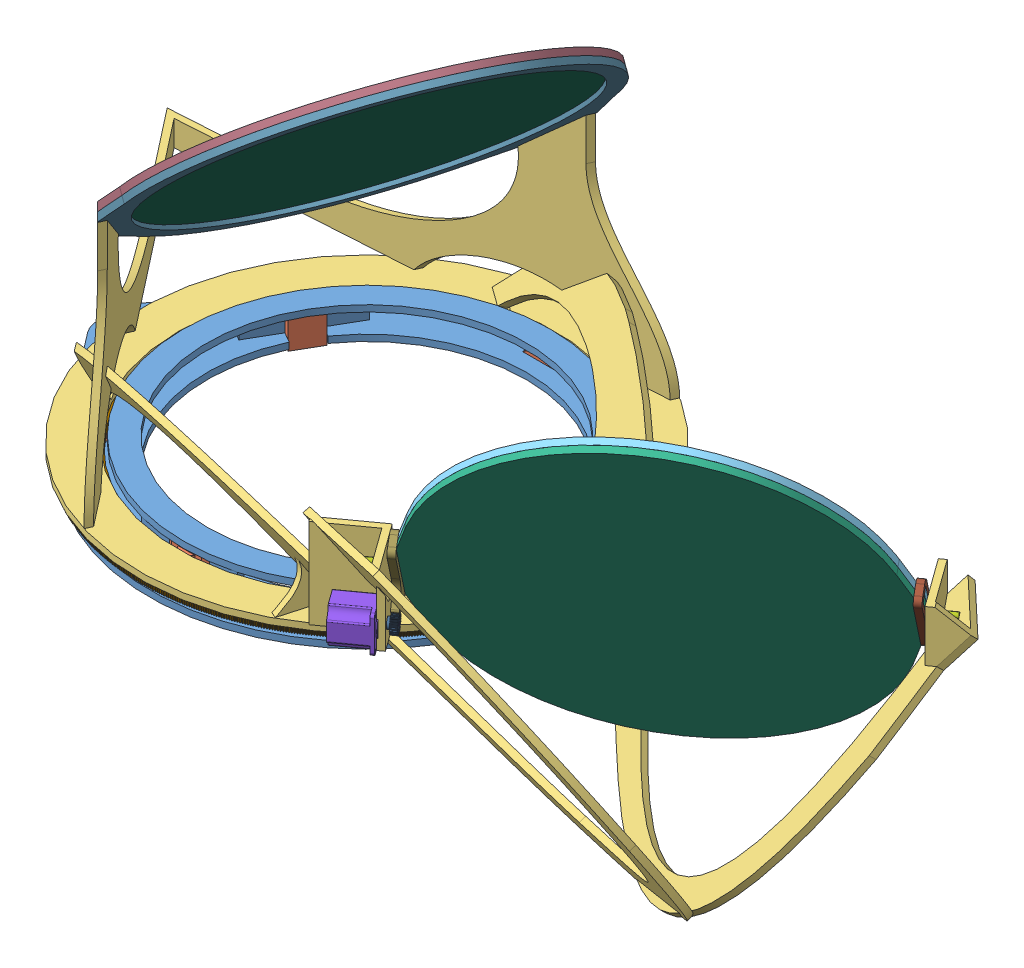
SolidWorks assembly Base assembly, configuration Default. Lengths in mm.
Overall size (1914.99 823.14 1392.98).
25 component instances, 15 part files, 49 mates.
Components (placement in the parent):
- Base-1: Base [Default] at (-52.5537 -31.3626 49.0391) size (745.7 50 680)
- McMaster 2303T11-1: McMaster 2303T11 [Default] at (-309.9581 -23.7438 197.6516) x (0.5 0 0.866025) z (-0.866025 0 0.5) size (62.32 36.6 44.45)
- McMaster 2303T11-2: McMaster 2303T11 [Default] at (-52.5537 -14.6635 323.9579) x (1 0 0) z (0 -1 0) size (62.32 36.6 44.45)
- McMaster 2303T11-3: McMaster 2303T11 [Default] at (-52.5537 -23.7438 -248.1859) size (62.32 36.6 44.45)
- McMaster 2303T11-4: McMaster 2303T11 [Default] at (204.8507 -23.7438 197.6516) x (0.5 0 -0.866025) z (0.866025 0 0.5) size (62.32 36.6 44.45)
- McMaster 2303T11-5: McMaster 2303T11 [Default] at (185.5329 -14.6635 -88.4202) x (0.5 0 0.866025) z (0 1 0) size (62.32 36.6 44.45)
- McMaster 2303T11-6: McMaster 2303T11 [Default] at (-290.6404 -14.6635 -88.4202) x (0.5 0 -0.866025) z (0 1 0) size (62.32 36.6 44.45)
- Plywood Construction-1-1: Plywood Construction-1 [Default] at (-52.5537 11.3374 49.0391) x (0.912295 0 0.409533) z (-0.409533 0 0.912295) size (1754.25 687.65 739.41)
- Mirror Assembly-2: Mirror Assembly [Default] at (781.8584 416.3374 423.6103) x (-0.810814 0 0.585304) z (-0.299925 -0.858731 -0.415482) size (600 20 760)
  - Mirror-1: Mirror [Default] at origin size (550 4 730)
  - Mirror Front-1: Mirror Front [Default] at origin size (600 10 760)
  - Mirror Back-1: Mirror Back [Default] x (-1 0 0) z (0 0 1) size (600 10 760)
- Primary Mirror Axle-1: Primary Mirror Axle [Default] at (1005.9697 404.2871 238.5997) x (0.299925 0.858731 0.415482) z (-0.502619 0.512426 -0.696271) size (40 45 20)
- Primary Mirror Axle-2: Primary Mirror Axle [Default] at (545.7501 394.0386 592.0016) x (0.299925 0.858731 0.415482) z (0.502619 -0.512426 0.696271) size (40 45 20)
- Stepper (Sparkfun 125oz)-1: Stepper (Sparkfun 125oz) [Default] at (509.4506 317.3629 674.4254) x (-0.585304 0 -0.810814) z (0 -1 0) size (56.4 77.1 56.4)
- Stepper (Sparkfun 125oz)-2: Stepper (Sparkfun 125oz) [Default] at (-443.2537 -75.3626 20.8391) x (0 0 1) z (-1 0 0) size (56.4 77.1 56.4)
- 700 teeth-1: 700 teeth [Gear Blank] at (-52.5537 1.3374 49.0391) x (0.924366 0 -0.381507) z (0 -1 0) size (702 702 10)
- A1Z2MYZ1002506-1: A1Z2MYZ1002506 [Default] at (-415.0537 -5.1626 49.0391) x (0 -1 0) z (0.987676 0 0.156512) size (17.51 26.95 26.99)
- A1Z2MYZ1002506-2: A1Z2MYZ1002506 [Default] at (551.8101 345.5629 609.0673) x (-0.810814 0 0.585304) z (0.490533 0.545544 0.679529) size (17.51 26.95 26.99)
- El mirror side bracket-2: El mirror side bracket [Default] at (1015.9029 355.8461 235.2748) x (0.299925 0.858731 0.415482) z (0.502619 -0.512426 0.696271) size (120 10 35)
- Gear_Blank_V2-1: Gear_Blank_V2 [Gear Blank] at (546.7224 416.3374 593.3485) x (0.502619 -0.512426 0.696271) z (-0.810814 0 0.585304) size (60.92 121 10)
- Secondary Mirror-1: Secondary Mirror [Default] at (82.1211 342.156 -39.8262) x (0.409533 0 -0.912295) z (0.64509 0.707107 0.289584) size (853.84 20 760)
  - Secondary Mirror Back-1: Secondary Mirror Back [Default] at (-136.2253 113.5977 -8.6893) size (591.15 10 760)
  - Secondary Mirror Front-1: Secondary Mirror Front [Default] at (-136.2253 113.5977 -8.6893) x (-1 0 0) z (0 0 1) size (592.25 10 760)
  - Secondary Mirror-1: Secondary Mirror [Default] at (-136.2253 113.5977 -8.6893) x (-1 0 0) z (0 0 1) size (832.72 4 730)
Mates (geometry in assembly coordinates):
- Coincident1: coincident anti-aligned: plane of Base-1 through (-318.0931 -21.3626 228.0116) normal (-0.5 0 -0.866025); plane of McMaster 2303T11-1 through (-318.0931 -21.3626 228.0116) normal (0.5 0 0.866025)
- Coincident2: coincident anti-aligned: plane of Base-1 through (-279.5982 -21.3626 205.7866) normal (-0.866025 0 0.5); plane of McMaster 2303T11-1 through (-290.7107 -23.7438 186.5391) normal (0.866025 0 -0.5)
- Coincident3: coincident anti-aligned: plane of Base-1 through (-52.5537 -21.3626 49.0391) normal (0 1 0); plane of McMaster 2303T11-1 through (-344.7855 -21.3626 181.7789) normal (0 -1 0)
- Coincident4: coincident anti-aligned: plane of Base-1 through (-30.3287 7.5615 296.3391) normal (-1 0 0); plane of McMaster 2303T11-2 through (-30.3287 -36.8885 326.3391) normal (1 0 0)
- Coincident5: coincident anti-aligned: plane of Base-1 through (-30.3287 7.5615 296.3391) normal (0 -1 0); plane of McMaster 2303T11-2 through (-52.5537 7.5615 323.9579) normal (0 1 0)
- Coincident6: coincident: plane of Base-1 through (-30.3037 18.6374 326.3391) normal (0 0 1); plane of McMaster 2303T11-2 through (-83.7136 -36.8885 326.3391) normal (0 0 -1)
- Coincident7: coincident anti-aligned: plane of Base-1 through (-74.7787 -21.3626 -270.4109) normal (0 0 1); plane of McMaster 2303T11-3 through (-52.5537 -23.7438 -270.4109) normal (0 0 -1)
- Coincident8: coincident anti-aligned: plane of Base-1 through (-52.5537 -21.3626 49.0391) normal (0 1 0); plane of McMaster 2303T11-3 through (-21.3939 -21.3626 -225.9609) normal (0 -1 0)
- Coincident9: coincident anti-aligned: plane of Base-1 through (-30.3287 -21.3626 -270.4109) normal (-1 0 0); plane of McMaster 2303T11-3 through (-30.3287 -21.3626 -225.9609) normal (1 0 0)
- Coincident10: coincident anti-aligned: plane of Base-1 through (196.7157 -21.3626 167.2917) normal (0.866025 0 0.5); plane of McMaster 2303T11-4 through (185.6032 -23.7438 186.5391) normal (-0.866025 0 -0.5)
- Coincident11: coincident anti-aligned: plane of Base-1 through (235.2106 -21.3626 189.5167) normal (-0.5 0 0.866025); plane of McMaster 2303T11-4 through (235.2106 -21.3626 189.5167) normal (0.5 0 -0.866025)
- Coincident12: coincident anti-aligned: plane of Base-1 through (-52.5537 -21.3626 49.0391) normal (0 1 0); plane of McMaster 2303T11-4 through (208.5182 -21.3626 235.7494) normal (0 -1 0)
- Coincident13: coincident anti-aligned: plane of Base-1 through (150.5018 7.5615 -93.8583) normal (0 -1 0); plane of McMaster 2303T11-5 through (185.5329 7.5615 -88.4202) normal (0 1 0)
- Coincident14: coincident anti-aligned: plane of Base-1 through (172.7268 7.5615 -55.3634) normal (-0.5 0 -0.866025); plane of McMaster 2303T11-5 through (198.7076 7.5615 -70.3634) normal (0.5 0 0.866025)
- Coincident15: coincident anti-aligned: plane of Base-1 through (176.4701 18.6374 -108.8799) normal (0.866025 0 -0.5); plane of McMaster 2303T11-5 through (172.0152 7.5615 -116.5961) normal (-0.866025 0 0.5)
- Coincident16: coincident anti-aligned: plane of Base-1 through (-255.6093 7.5615 -93.8583) normal (-0.5 0 0.866025); plane of McMaster 2303T11-6 through (-281.5901 7.5615 -108.8583) normal (0.5 0 -0.866025)
- Coincident17: coincident anti-aligned: plane of Base-1 through (-277.8343 7.5615 -55.3634) normal (0 -1 0); plane of McMaster 2303T11-6 through (-290.6404 7.5615 -88.4202) normal (0 1 0)
- Coincident18: coincident anti-aligned: plane of Base-1 through (-303.8276 18.6374 -70.3418) normal (-0.866025 0 -0.5); plane of McMaster 2303T11-6 through (-277.1227 7.5615 -116.5961) normal (0.866025 0 0.5)
- Concentric3: concentric aligned: circle of Base-1; circle of Plywood Construction-1-1
- Concentric4: concentric anti-aligned: circle of Plywood Construction-1-1; circle of Mirror Assembly-2/Mirror Back-1
- Concentric5: concentric anti-aligned: circle of Plywood Construction-1-1; circle of Primary Mirror Axle-1
- Coincident25: coincident aligned: plane of Mirror Assembly-2/Mirror Front-1 through (776.8322 421.4617 416.6476) normal (-0.502619 0.512426 -0.696271); plane of Primary Mirror Axle-1 through (1015.2776 407.722 234.4086) normal (-0.502619 0.512426 -0.696271)
- Concentric6: concentric aligned: circle of Plywood Construction-1-1; circle of Primary Mirror Axle-2
- Coincident27: coincident aligned: plane of Mirror Assembly-2/Mirror Front-1 through (776.8322 421.4617 416.6476) normal (-0.502619 0.512426 -0.696271); plane of Primary Mirror Axle-2 through (528.7893 407.722 585.5911) normal (-0.502619 0.512426 -0.696271)
- Coincident28: coincident anti-aligned: plane of Plywood Construction-1-1 through (556.1463 456.3374 646.8525) normal (-0.810814 0 0.585304); plane of Stepper (Sparkfun 125oz)-1 through (550.5246 369.1329 639.0649) normal (0.810814 0 -0.585304)
- Parallel2: parallel aligned: plane of Stepper (Sparkfun 125oz)-1 through (550.5246 317.3629 639.0649) normal (0 -1 0); plane of Plywood Construction-1-1 through (451.0265 316.3374 641.0669) normal (0 -1 0)
- Coincident38: coincident: line of Stepper (Sparkfun 125oz)-2 through (-434.1037 -19.7626 49.0391) axis (1 0 0); plane of Base-1 through (-52.5537 -31.3626 49.0391) normal (0 0 1)
- Coincident41: coincident anti-aligned: plane of Plywood Construction-1-1 through (-52.5537 1.3374 49.0391) normal (0 -1 0); plane of 700 teeth-1 through (80.653 1.3374 373.3095) normal (0 1 0)
- Concentric7: concentric aligned: circle of Base-1; circle of 700 teeth-1
- Concentric8: concentric aligned: cylinder of Stepper (Sparkfun 125oz)-2 through (-415.0537 1.7374 49.0391) axis (0 -1 0) radius 3.175; circle of A1Z2MYZ1002506-1
- Tangent1: tangent anti-aligned: cylinder of McMaster 2303T11-1 through (-329.2056 -23.7438 208.7641) axis (0.866025 0 -0.5) radius 15.0812; plane of 700 teeth-1 through (80.653 -8.6626 373.3095) normal (0 -1 0)
- Distance4: distance = 362.5 mm: point of Stepper (Sparkfun 125oz)-2; line of 700 teeth-1 through (-52.5537 1.8374 49.0391) axis (0 -1 0)
- Distance5: distance = 2 mm anti-aligned: plane of A1Z2MYZ1002506-1 through (-415.0537 -0.6626 49.0391) normal (0 1 0); plane of Plywood Construction-1-1 through (-52.5537 1.3374 49.0391) normal (0 -1 0)
- Coincident50: coincident aligned: plane of Base-1 through (-52.5537 -21.3626 49.0391) normal (0 1 0); plane of Stepper (Sparkfun 125oz)-2 through (-391.4837 -21.3626 25.4691) normal (0 1 0)
- Concentric9: concentric aligned: cylinder of Stepper (Sparkfun 125oz)-1 through (555.4588 345.5629 606.4335) axis (-0.810814 0 0.585304) radius 3.175; cylinder of A1Z2MYZ1002506-2 through (556.1682 345.5629 605.9213) axis (-0.810814 0 0.585304) radius 3
- Coincident51: coincident aligned: plane of Stepper (Sparkfun 125oz)-1 through (555.4588 345.5629 606.4335) normal (0.810814 0 -0.585304); plane of A1Z2MYZ1002506-2 through (555.4588 345.5629 606.4335) normal (0.810814 0 -0.585304)
- Coincident52: coincident: point of Plywood Construction-1-1; plane of ?
- Coincident58: coincident anti-aligned: plane of Mirror Assembly-2/Mirror Back-1 through (1034.9899 467.8613 278.801) normal (0.810814 0 -0.585304); plane of El mirror side bracket-2 through (1005.7678 369.5577 238.32) normal (-0.810814 0 0.585304)
- Coincident60: coincident anti-aligned: plane of Mirror Assembly-2/Mirror Back-1 through (786.8846 411.2132 430.573) normal (0.502619 -0.512426 0.696271); plane of El mirror side bracket-2 through (1037.0169 454.1497 281.6089) normal (-0.502619 0.512426 -0.696271)
- Coincident61: coincident anti-aligned: plane of Mirror Assembly-2/Mirror Back-1 through (1040.0988 459.274 268.7931) normal (0.299925 0.858731 0.415482); plane of El mirror side bracket-2 through (1026.9645 464.3983 267.6834) normal (-0.299925 -0.858731 -0.415482)
- Concentric11: concentric anti-aligned: circle of Plywood Construction-1-1; cylinder of Stepper (Sparkfun 125oz)-1 through (555.4588 345.5629 606.4335) axis (-0.810814 0 0.585304) radius 3.175
- Concentric12: concentric anti-aligned: cylinder of Primary Mirror Axle-2 through (523.2088 416.3374 610.3223) axis (0.810814 0 -0.585304) radius 5; circle of Gear_Blank_V2-1
- Coincident66: coincident anti-aligned: plane of Mirror Assembly-2/Mirror Front-1 through (547.6948 438.6363 594.6954) normal (-0.810814 0 0.585304); plane of Gear_Blank_V2-1 through (564.5742 468.6108 618.0783) normal (0.810814 0 -0.585304)
- Parallel6: parallel aligned: plane of Mirror Assembly-2/Mirror Front-1 through (776.8322 421.4617 416.6476) normal (-0.502619 0.512426 -0.696271); plane of Gear_Blank_V2-1 through (552.9229 468.2415 601.9379) normal (-0.502619 0.512426 -0.696271)
- Coincident70: coincident anti-aligned: plane of Mirror Assembly-2/Mirror Front-1 through (1017.9667 438.6363 255.219) normal (0.810814 0 -0.585304); plane of Primary Mirror Axle-1 through (1024.8089 427.0026 264.6974) normal (-0.810814 0 0.585304)
- Coincident71: coincident anti-aligned: plane of Mirror Assembly-2/Mirror Front-1 through (547.6948 438.6363 594.6954) normal (-0.810814 0 0.585304); plane of Primary Mirror Axle-2 through (548.5055 433.1517 595.8186) normal (0.810814 0 -0.585304)
- Coincident78: coincident: point of Plywood Construction-1-1; point of ?
- Parallel8: parallel: line of Plywood Construction-1-1 through (-280.6275 166.3374 -53.3441) axis (0.64509 0.707107 0.289584); plane of ? through (-49.9734 413.509 50.1975) normal (0.64509 -0.707107 0.289584)
- Coincident80: coincident: point of Plywood Construction-1-1; line of ? through (-52.5537 416.3374 49.0391) axis (-0.409533 0 0.912295)
